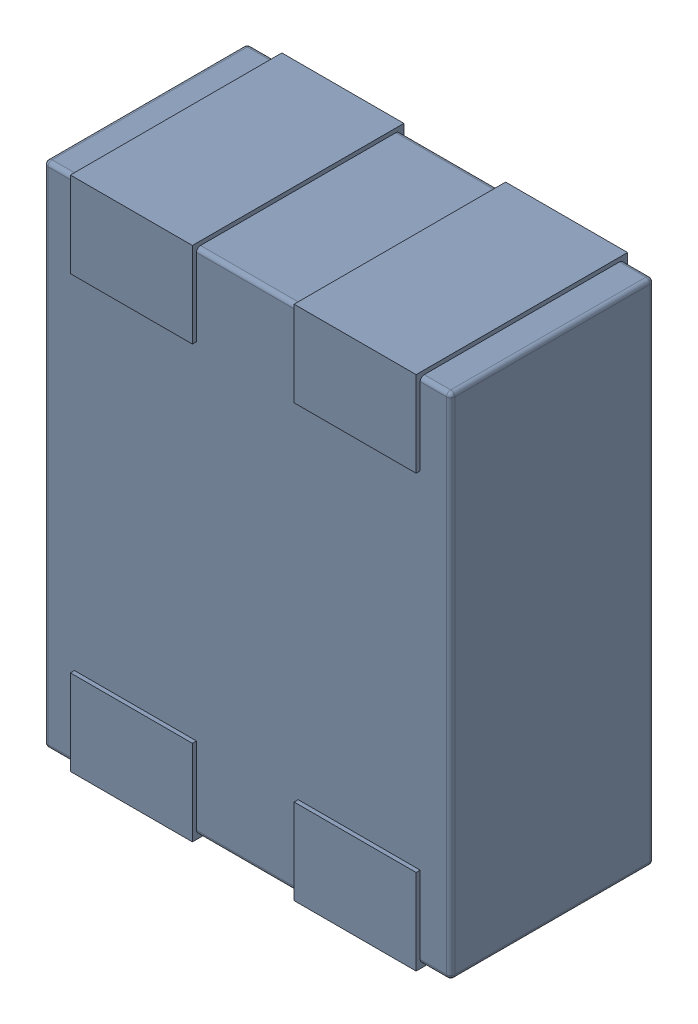
SolidWorks assembly L6, configuration Défaut. Lengths in mm.
Overall size (1 1.27 0.52).
4 component instances, 1 part files, 0 mates.
Components (placement in the parent):
- MCZ1210DH900L2TA0G-1: MCZ1210DH900L2TA0G [Défaut] at (45.7003 -40.5265 -1.6) x (-1 0 0) z (0 0 1) size (1 1.27 0.52)
  - 3D_PCB1_2021-12-30 (1).step-1: 3D_PCB1_2021-12-30 (1).step [Défaut] at origin size (1 1.27 0.52)
    - a3ec64f90eb5404ebd79eca0046a794a.step-1: a3ec64f90eb5404ebd79eca0046a794a.step [Défaut] at (5.0419 -6.8961 1.6) size (1 1.27 0.52)
      - SOLID.step_650-1: SOLID.step_650 [Défaut] at origin size (1 1.27 0.52)
